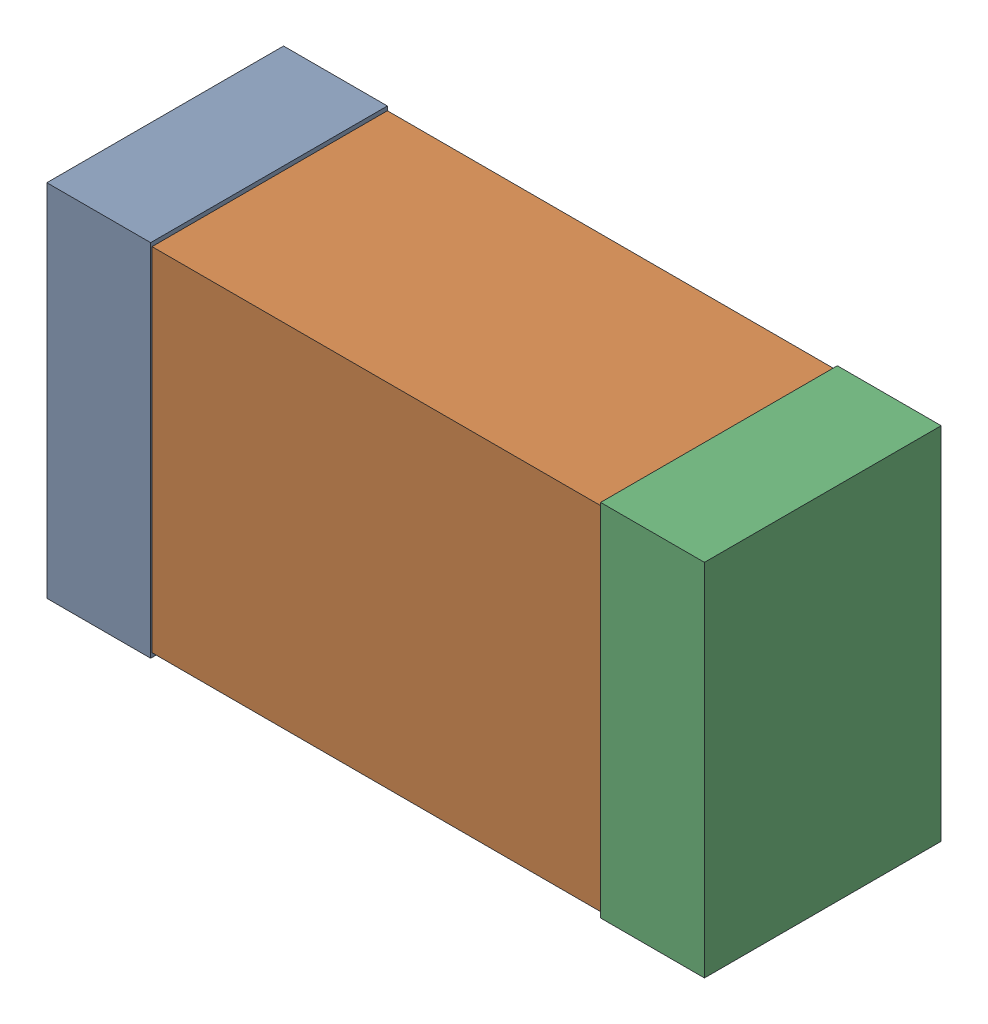
SolidWorks assembly C14_Motor_2Kanaloa_v2.0.0_Motor, configuration Default. Lengths in mm.
Overall size (2.38 1.3 0.85).
6 component instances, 2 part files, 0 mates.
Components (placement in the parent):
- 352877648-1: 352877648 [Default] at (119.348 55.88 0) size (0.38 1.3 0.85)
  - Extruded_14-1: Extruded_14 [Default] at origin size (0.38 1.3 0.85)
- 352877392-1: 352877392 [Default] at (120.348 55.88 0) size (2.2 1.27 0.85)
  - Extruded_15-1: Extruded_15 [Default] at origin size (2.2 1.27 0.85)
- 352877648-2: 352877648 [Default] at (121.348 55.88 0) size (0.38 1.3 0.85)
  - Extruded_14-1: Extruded_14 [Default] at origin size (0.38 1.3 0.85)
